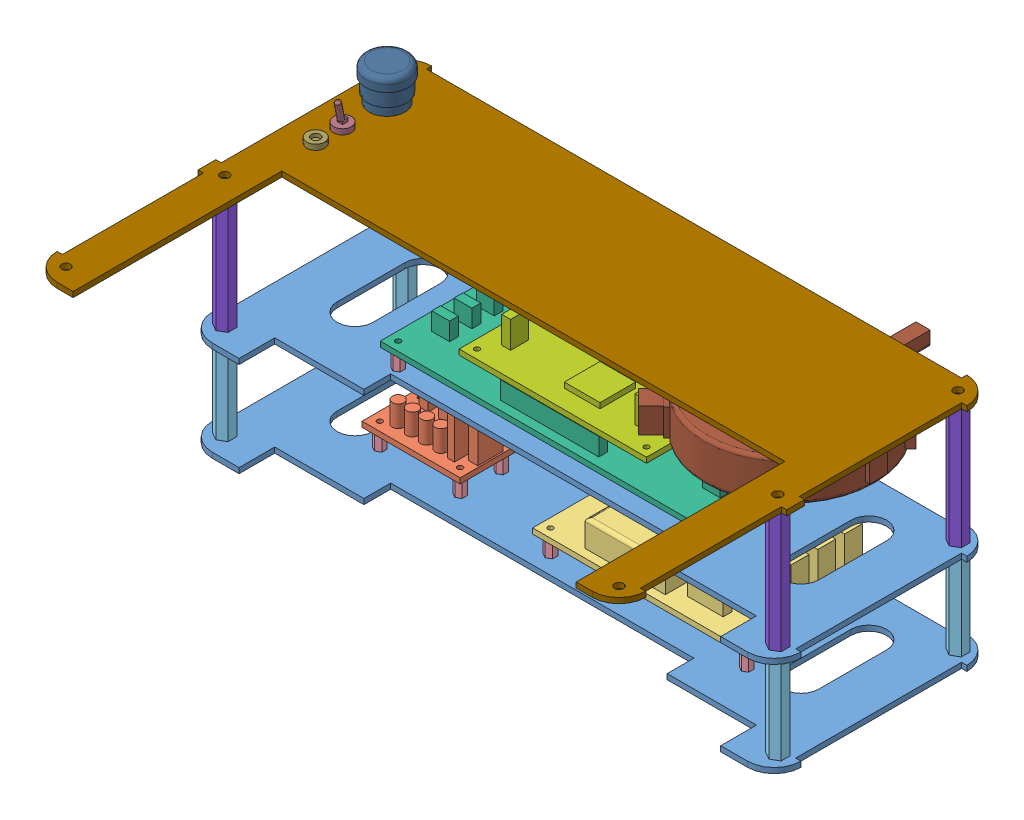
SolidWorks assembly plaque_electronique_2, configuration Default. Lengths in mm.
Overall size (342.02 149 236).
36 component instances, 13 part files, 75 mates.
Components (placement in the parent):
- plaque_plastique_L330_l123_decoupe_servos-4: plaque_plastique_L330_l123_decoupe_servos [Défaut] at (-146.0053 45.2677 19.7035) size (330 3 123)
- carte_hacheur-1: carte_hacheur [Default] at (-91.0726 58.2677 -67.2965) size (55 26 33)
- carte_hacheur-2: carte_hacheur [Default] at (-91.0726 58.2677 -24.2965) size (55 26 33)
- carte_puissance_2-1: carte_puissance_2 [Default] at (8.5605 58.2677 -20.2965) size (120 28 80)
- entretoise_M3_L10-1: entretoise_M3_L10 [Default] at (-86.0726 48.2677 -72.2965) size (5.2 10 6)
- entretoise_M3_L10-2: entretoise_M3_L10 [Default] at (-41.0726 48.2677 -52.2965) size (5.2 10 6)
- entretoise_M3_L10-3: entretoise_M3_L10 [Default] at (-86.0726 48.2677 -29.2965) size (5.2 10 6)
- entretoise_M3_L10-4: entretoise_M3_L10 [Default] at (13.5605 48.2677 -95.2965) size (5.2 10 6)
- entretoise_M3_L10-5: entretoise_M3_L10 [Default] at (-86.0726 48.2677 -52.2965) size (5.2 10 6)
- entretoise_M3_L10-6: entretoise_M3_L10 [Default] at (-86.0726 48.2677 -95.2965) size (5.2 10 6)
- entretoise_M3_L10-7: entretoise_M3_L10 [Default] at (-41.0726 48.2677 -29.2965) size (5.2 10 6)
- entretoise_M3_L10-8: entretoise_M3_L10 [Default] at (123.5605 48.2677 -25.2965) size (5.2 10 6)
- entretoise_M3_L10-9: entretoise_M3_L10 [Default] at (13.5605 48.2677 -25.2965) size (5.2 10 6)
- entretoise_M3_L10-10: entretoise_M3_L10 [Default] at (123.5605 48.2677 -95.2965) size (5.2 10 6)
- entretoise_M3_L10-11: entretoise_M3_L10 [Default] at (-41.0726 48.2677 -72.2965) size (5.2 10 6)
- entretoise_M3_L10-12: entretoise_M3_L10 [Default] at (-41.0726 48.2677 -95.2965) size (5.2 10 6)
- plaque_plastique_L330_l123_decoupe_servos-3: plaque_plastique_L330_l123_decoupe_servos [Défaut] at (-146.0053 98.2677 19.7035) size (330 3 123)
- entretoise_M5_L50-12: entretoise_M5_L50 [Default] at (-136.0053 48.2677 7.7035) size (8.66 50 10)
- entretoise_M5_L50-11: entretoise_M5_L50 [Default] at (173.9947 48.2677 7.7035) size (8.66 50 10)
- entretoise_M5_L50-10: entretoise_M5_L50 [Default] at (-136.0053 48.2677 -93.2965) size (8.66 50 10)
- entretoise_M5_L50-13: entretoise_M5_L50 [Default] at (173.9947 48.2677 -93.2965) size (8.66 50 10)
- carte_interface_2-1: carte_interface_2 [Default] at (108.1542 111.2677 -100.2965) x (-1 0 0) z (0 0 -1) size (180 13 85)
- carte_PIC32_FPGA-1: carte_PIC32_FPGA [Default] at (75.1237 127.2677 -97.5564) x (-1 0 0) z (0 0 -1) size (115 28 80)
- entretoise_M3_L10-13: entretoise_M3_L10 [Default] at (103.1542 101.2677 -95.2965) size (5.2 10 6)
- entretoise_M3_L10-14: entretoise_M3_L10 [Default] at (-66.8458 101.2677 -95.2965) size (5.2 10 6)
- entretoise_M3_L10-15: entretoise_M3_L10 [Default] at (-66.8458 101.2677 -20.2965) size (5.2 10 6)
- entretoise_M3_L10-16: entretoise_M3_L10 [Default] at (103.1542 101.2677 -20.2965) size (5.2 10 6)
- entretoise_M5_L70-16: entretoise_M5_L70 [Default] at (-136.0053 101.2677 7.7035) size (8.66 70 10)
- entretoise_M5_L70-14: entretoise_M5_L70 [Default] at (-136.0053 101.2677 -93.2965) size (8.66 70 10)
- entretoise_M5_L70-15: entretoise_M5_L70 [Default] at (173.9947 101.2677 7.7035) size (8.66 70 10)
- entretoise_M5_L70-17: entretoise_M5_L70 [Default] at (173.9947 101.2677 -93.2965) size (8.66 70 10)
- plaque_plastique_L330_l210_decoupe_dessus-1: plaque_plastique_L330_l210_decoupe_dessus [Défaut] at (-146.0053 171.2677 106.7035) size (330 3 210)
- arret_urgence-1: arret_urgence [Default] at (-126.0053 187.2677 -73.2965) x (0.976487 0 -0.215576) z (0.215576 0 0.976487) size (24 42 24)
- ICD2-1: ICD2 [Default] at (158.082 167.2677 -85.6528) x (0.707107 0 0.707107) z (0.707107 0 -0.707107) size (104.08 23 115.65)
- jack_tirette-4: jack_tirette [Défaut] at (-126.0053 174.2677 -33.2965) size (10 21 12)
- bouton_levier-3: bouton_levier [Défaut] at (-126.0053 174.2677 -48.2965) size (10 32.55 12)
Mates (geometry in assembly coordinates):
- Coïncidente1: coincident anti-aligned: plane of carte_hacheur-1 through (-91.0726 58.2677 -100.2965) normal (0 -1 0); plane of entretoise_M3_L10-1 through (-86.0726 58.2677 -75.2965) normal (0 1 0)
- Coïncidente2: coincident anti-aligned: plane of carte_hacheur-1 through (-91.0726 58.2677 -100.2965) normal (0 -1 0); plane of entretoise_M3_L10-6 through (-86.0726 58.2677 -98.2965) normal (0 1 0)
- Coïncidente3: coincident anti-aligned: plane of carte_hacheur-1 through (-91.0726 58.2677 -100.2965) normal (0 -1 0); plane of entretoise_M3_L10-11 through (-41.0726 58.2677 -75.2965) normal (0 1 0)
- Coïncidente4: coincident anti-aligned: plane of carte_hacheur-1 through (-91.0726 58.2677 -100.2965) normal (0 -1 0); plane of entretoise_M3_L10-12 through (-41.0726 58.2677 -98.2965) normal (0 1 0)
- Coaxiale1: concentric aligned: cylinder of carte_hacheur-1; cylinder of entretoise_M3_L10-1
- Coaxiale2: concentric aligned: cylinder of carte_hacheur-1; cylinder of entretoise_M3_L10-6
- Coaxiale3: concentric aligned: cylinder of carte_hacheur-1; cylinder of entretoise_M3_L10-11
- Coaxiale4: concentric aligned: cylinder of carte_hacheur-1; cylinder of entretoise_M3_L10-12
- Coïncidente5: coincident anti-aligned: plane of carte_hacheur-2 through (-91.0726 58.2677 -57.2965) normal (0 -1 0); plane of entretoise_M3_L10-2 through (-41.0726 58.2677 -55.2965) normal (0 1 0)
- Coïncidente6: coincident anti-aligned: plane of carte_hacheur-2 through (-91.0726 58.2677 -57.2965) normal (0 -1 0); plane of entretoise_M3_L10-7 through (-41.0726 58.2677 -32.2965) normal (0 1 0)
- Coïncidente7: coincident anti-aligned: plane of carte_hacheur-2 through (-91.0726 58.2677 -57.2965) normal (0 -1 0); plane of entretoise_M3_L10-3 through (-86.0726 58.2677 -32.2965) normal (0 1 0)
- Coïncidente8: coincident anti-aligned: plane of carte_hacheur-2 through (-91.0726 58.2677 -57.2965) normal (0 -1 0); plane of entretoise_M3_L10-5 through (-86.0726 58.2677 -55.2965) normal (0 1 0)
- Coaxiale5: concentric aligned: cylinder of carte_hacheur-2; cylinder of entretoise_M3_L10-3
- Coaxiale6: concentric aligned: cylinder of carte_hacheur-2; cylinder of entretoise_M3_L10-5
- Coaxiale7: concentric aligned: cylinder of carte_hacheur-2; cylinder of entretoise_M3_L10-2
- Coaxiale8: concentric aligned: cylinder of carte_hacheur-2; cylinder of entretoise_M3_L10-7
- Coïncidente9: coincident anti-aligned: plane of carte_puissance_2-1 through (8.5605 58.2677 -100.2965) normal (0 -1 0); plane of entretoise_M3_L10-4 through (13.5605 58.2677 -98.2965) normal (0 1 0)
- Coïncidente10: coincident anti-aligned: plane of carte_puissance_2-1 through (8.5605 58.2677 -100.2965) normal (0 -1 0); plane of entretoise_M3_L10-8 through (123.5605 58.2677 -28.2965) normal (0 1 0)
- Coïncidente11: coincident anti-aligned: plane of carte_puissance_2-1 through (8.5605 58.2677 -100.2965) normal (0 -1 0); plane of entretoise_M3_L10-10 through (123.5605 58.2677 -98.2965) normal (0 1 0)
- Coïncidente12: coincident anti-aligned: plane of carte_puissance_2-1 through (8.5605 58.2677 -100.2965) normal (0 -1 0); plane of entretoise_M3_L10-9 through (13.5605 58.2677 -28.2965) normal (0 1 0)
- Coaxiale9: concentric aligned: cylinder of carte_puissance_2-1; cylinder of entretoise_M3_L10-9
- Coaxiale10: concentric aligned: cylinder of carte_puissance_2-1; cylinder of entretoise_M3_L10-4
- Coaxiale11: concentric aligned: cylinder of carte_puissance_2-1; cylinder of entretoise_M3_L10-8
- Coaxiale12: concentric aligned: cylinder of carte_puissance_2-1; cylinder of entretoise_M3_L10-10
- Coïncidente17: coincident aligned: plane of carte_hacheur-1 through (-91.0726 61.2677 -100.2965) normal (0 0 -1); plane of carte_puissance_2-1 through (8.5605 61.2677 -100.2965) normal (0 0 -1)
- Distance2: distance = 10 mm anti-aligned: plane of carte_hacheur-2 through (-91.0726 61.2677 -57.2965) normal (0 0 -1); plane of carte_hacheur-1 through (-91.0726 61.2677 -67.2965) normal (0 0 1)
- Coïncidente19: coincident aligned: plane of carte_hacheur-1 through (-36.0726 61.2677 -67.2965) normal (1 0 0); plane of carte_hacheur-2 through (-36.0726 61.2677 -24.2965) normal (1 0 0)
- Coïncidente20: coincident anti-aligned: plane of plaque_plastique_L330_l123_decoupe_servos-4 through (-146.0053 48.2677 -103.2965) normal (0 1 0); plane of entretoise_M5_L50-12 through (-136.0053 48.2677 2.7035) normal (0 -1 0)
- Coïncidente21: coincident anti-aligned: plane of plaque_plastique_L330_l123_decoupe_servos-4 through (-146.0053 48.2677 -103.2965) normal (0 1 0); plane of entretoise_M5_L50-10 through (-136.0053 48.2677 -98.2965) normal (0 -1 0)
- Coïncidente22: coincident anti-aligned: plane of plaque_plastique_L330_l123_decoupe_servos-4 through (-146.0053 48.2677 -103.2965) normal (0 1 0); plane of entretoise_M5_L50-11 through (173.9947 48.2677 2.7035) normal (0 -1 0)
- Coïncidente23: coincident anti-aligned: plane of plaque_plastique_L330_l123_decoupe_servos-4 through (-146.0053 48.2677 -103.2965) normal (0 1 0); plane of entretoise_M5_L50-13 through (173.9947 48.2677 -98.2965) normal (0 -1 0)
- Coaxiale14: concentric aligned: cylinder of plaque_plastique_L330_l123_decoupe_servos-4; cylinder of entretoise_M5_L50-10
- Coaxiale15: concentric aligned: cylinder of plaque_plastique_L330_l123_decoupe_servos-4; cylinder of entretoise_M5_L50-12
- Coaxiale16: concentric aligned: cylinder of plaque_plastique_L330_l123_decoupe_servos-4; cylinder of entretoise_M5_L50-11
- Coaxiale17: concentric aligned: cylinder of plaque_plastique_L330_l123_decoupe_servos-4; cylinder of entretoise_M5_L50-13
- Coaxiale18: concentric aligned: cylinder of plaque_plastique_L330_l123_decoupe_servos-3; cylinder of entretoise_M5_L50-10
- Coïncidente24: coincident anti-aligned: plane of plaque_plastique_L330_l123_decoupe_servos-3 through (-146.0053 98.2677 -103.2965) normal (0 -1 0); plane of entretoise_M5_L50-10 through (-136.0053 98.2677 -98.2965) normal (0 1 0)
- Coaxiale19: concentric aligned: cylinder of plaque_plastique_L330_l123_decoupe_servos-3; cylinder of entretoise_M5_L50-12
- Coïncidente26: coincident aligned: plane of carte_interface_2-1 through (45.6542 124.2677 -95.2965) normal (0 0 -1); plane of carte_PIC32_FPGA-1 through (32.9398 117.2677 -95.2965) normal (0 0 -1)
- Coïncidente27: coincident aligned: plane of carte_interface_2-1 through (-9.3458 124.2677 -90.2965) normal (-1 0 0); plane of carte_PIC32_FPGA-1 through (-9.3458 117.2677 -95.2965) normal (-1 0 0)
- Coïncidente28: coincident anti-aligned: plane of carte_interface_2-1 through (108.1542 111.2677 -15.2965) normal (0 -1 0); plane of entretoise_M3_L10-13 through (103.1542 111.2677 -98.2965) normal (0 1 0)
- Coïncidente29: coincident anti-aligned: plane of carte_interface_2-1 through (108.1542 111.2677 -15.2965) normal (0 -1 0); plane of entretoise_M3_L10-14 through (-66.8458 111.2677 -98.2965) normal (0 1 0)
- Coïncidente30: coincident anti-aligned: plane of carte_interface_2-1 through (108.1542 111.2677 -15.2965) normal (0 -1 0); plane of entretoise_M3_L10-16 through (103.1542 111.2677 -23.2965) normal (0 1 0)
- Coïncidente31: coincident anti-aligned: plane of carte_interface_2-1 through (108.1542 111.2677 -15.2965) normal (0 -1 0); plane of entretoise_M3_L10-15 through (-66.8458 111.2677 -23.2965) normal (0 1 0)
- Coaxiale20: concentric aligned: cylinder of carte_interface_2-1; cylinder of entretoise_M3_L10-15
- Coaxiale21: concentric aligned: cylinder of carte_interface_2-1; cylinder of entretoise_M3_L10-16
- Coaxiale22: concentric aligned: cylinder of carte_interface_2-1; cylinder of entretoise_M3_L10-14
- Coaxiale23: concentric aligned: cylinder of carte_interface_2-1; cylinder of entretoise_M3_L10-13
- Coïncidente34: coincident anti-aligned: plane of plaque_plastique_L330_l123_decoupe_servos-3 through (-146.0053 101.2677 -103.2965) normal (0 1 0); plane of entretoise_M5_L70-16 through (-136.0053 101.2677 2.7035) normal (0 -1 0)
- Coïncidente35: coincident anti-aligned: plane of plaque_plastique_L330_l123_decoupe_servos-3 through (-146.0053 101.2677 -103.2965) normal (0 1 0); plane of entretoise_M5_L70-14 through (-136.0053 101.2677 -98.2965) normal (0 -1 0)
- Coïncidente36: coincident anti-aligned: plane of plaque_plastique_L330_l123_decoupe_servos-3 through (-146.0053 101.2677 -103.2965) normal (0 1 0); plane of entretoise_M5_L70-15 through (173.9947 101.2677 2.7035) normal (0 -1 0)
- Coïncidente37: coincident anti-aligned: plane of plaque_plastique_L330_l123_decoupe_servos-3 through (-146.0053 101.2677 -103.2965) normal (0 1 0); plane of entretoise_M5_L70-17 through (173.9947 101.2677 -98.2965) normal (0 -1 0)
- Coaxiale24: concentric aligned: cylinder of plaque_plastique_L330_l123_decoupe_servos-3; cylinder of entretoise_M5_L70-17
- Coaxiale25: concentric aligned: cylinder of plaque_plastique_L330_l123_decoupe_servos-3; cylinder of entretoise_M5_L70-15
- Coaxiale26: concentric aligned: cylinder of plaque_plastique_L330_l123_decoupe_servos-3; cylinder of entretoise_M5_L70-14
- Coaxiale27: concentric aligned: cylinder of plaque_plastique_L330_l123_decoupe_servos-3; cylinder of entretoise_M5_L70-16
- Coïncidente38: coincident anti-aligned: plane of entretoise_M5_L70-14 through (-136.0053 171.2677 -98.2965) normal (0 1 0); plane of plaque_plastique_L330_l210_decoupe_dessus-1 through (-146.0053 171.2677 -103.2965) normal (0 -1 0)
- Coaxiale28: concentric aligned: cylinder of entretoise_M5_L70-14; cylinder of plaque_plastique_L330_l210_decoupe_dessus-1
- Coaxiale29: concentric anti-aligned: cylinder of plaque_plastique_L330_l210_decoupe_dessus-1; cylinder of arret_urgence-1
- Coïncidente40: coincident anti-aligned: plane of plaque_plastique_L330_l210_decoupe_dessus-1 through (-146.0053 174.2677 -103.2965) normal (0 1 0); plane of arret_urgence-1 through (-126.0053 174.2677 -73.2965) normal (0 -1 0)
- Coïncidente41: coincident aligned: plane of carte_puissance_2-1 through (8.5605 61.2677 -100.2965) normal (0 0 -1); plane of carte_interface_2-1 through (108.1542 114.2677 -100.2965) normal (0 0 -1)
- Coïncidente45: coincident aligned: plane of carte_hacheur-1 through (-91.0726 61.2677 -100.2965) normal (0 1 0); plane of carte_hacheur-2 through (-91.0726 61.2677 -57.2965) normal (0 1 0)
- Distance3: distance = 19 mm anti-aligned: plane of carte_PIC32_FPGA-1 through (75.1237 130.2677 -17.5564) normal (0 1 0); plane of carte_interface_2-1 through (108.1542 111.2677 -15.2965) normal (0 -1 0)
- Coïncidente47: coincident anti-aligned: plane of plaque_plastique_L330_l123_decoupe_servos-3 through (-146.0053 101.2677 -103.2965) normal (0 1 0); plane of entretoise_M3_L10-13 through (103.1542 101.2677 -98.2965) normal (0 -1 0)
- Coïncidente48: coincident anti-aligned: plane of plaque_plastique_L330_l123_decoupe_servos-4 through (-146.0053 48.2677 -103.2965) normal (0 1 0); plane of entretoise_M3_L10-10 through (123.5605 48.2677 -98.2965) normal (0 -1 0)
- Coïncidente49: coincident anti-aligned: plane of plaque_plastique_L330_l123_decoupe_servos-4 through (-146.0053 48.2677 -103.2965) normal (0 1 0); plane of entretoise_M3_L10-3 through (-86.0726 48.2677 -32.2965) normal (0 -1 0)
- Coïncidente53: coincident aligned: plane of plaque_plastique_L330_l123_decoupe_servos-3 through (-131.0053 98.2667 -100.2965) normal (0 0 -1); plane of plaque_plastique_L330_l210_decoupe_dessus-1 through (-131.0053 171.2667 -100.2965) normal (0 0 -1)
- Coïncidente54: coincident anti-aligned: plane of plaque_plastique_L330_l210_decoupe_dessus-1 through (-146.0053 171.2677 -103.2965) normal (0 -1 0); plane of ICD2-1 through (122.7267 171.2677 -50.2974) normal (0 1 0)
- Coïncidente55: coincident aligned: plane of plaque_plastique_L330_l210_decoupe_dessus-1 through (-131.0053 171.2667 -100.2965) normal (0 0 -1); plane of ICD2-1 through (117.4234 152.2677 -100.2965) normal (0 0 -1)
- Coïncidente56: coincident aligned: plane of plaque_plastique_L330_l123_decoupe_servos-4 through (-131.0053 45.2667 -100.2965) normal (0 0 -1); plane of carte_puissance_2-1 through (8.5605 61.2677 -100.2965) normal (0 0 -1)
- Coaxiale30: concentric anti-aligned: cylinder of plaque_plastique_L330_l210_decoupe_dessus-1; cylinder of bouton_levier-3
- Coïncidente57: coincident anti-aligned: plane of plaque_plastique_L330_l210_decoupe_dessus-1 through (-146.0053 174.2677 -103.2965) normal (0 1 0); plane of bouton_levier-3 through (-126.0053 174.2677 -48.2965) normal (0 -1 0)
- Coaxiale31: concentric anti-aligned: cylinder of plaque_plastique_L330_l210_decoupe_dessus-1; cylinder of jack_tirette-4
- Coïncidente58: coincident anti-aligned: plane of plaque_plastique_L330_l210_decoupe_dessus-1 through (-146.0053 174.2677 -103.2965) normal (0 1 0); plane of jack_tirette-4 through (-126.0053 174.2677 -33.2965) normal (0 -1 0)
- Coïncidente60: coincident aligned: plane of jack_tirette-4 through (-129.0053 161.2677 -39.2965) normal (-1 0 0); plane of bouton_levier-3 through (-129.0053 161.2677 -54.2965) normal (-1 0 0)
